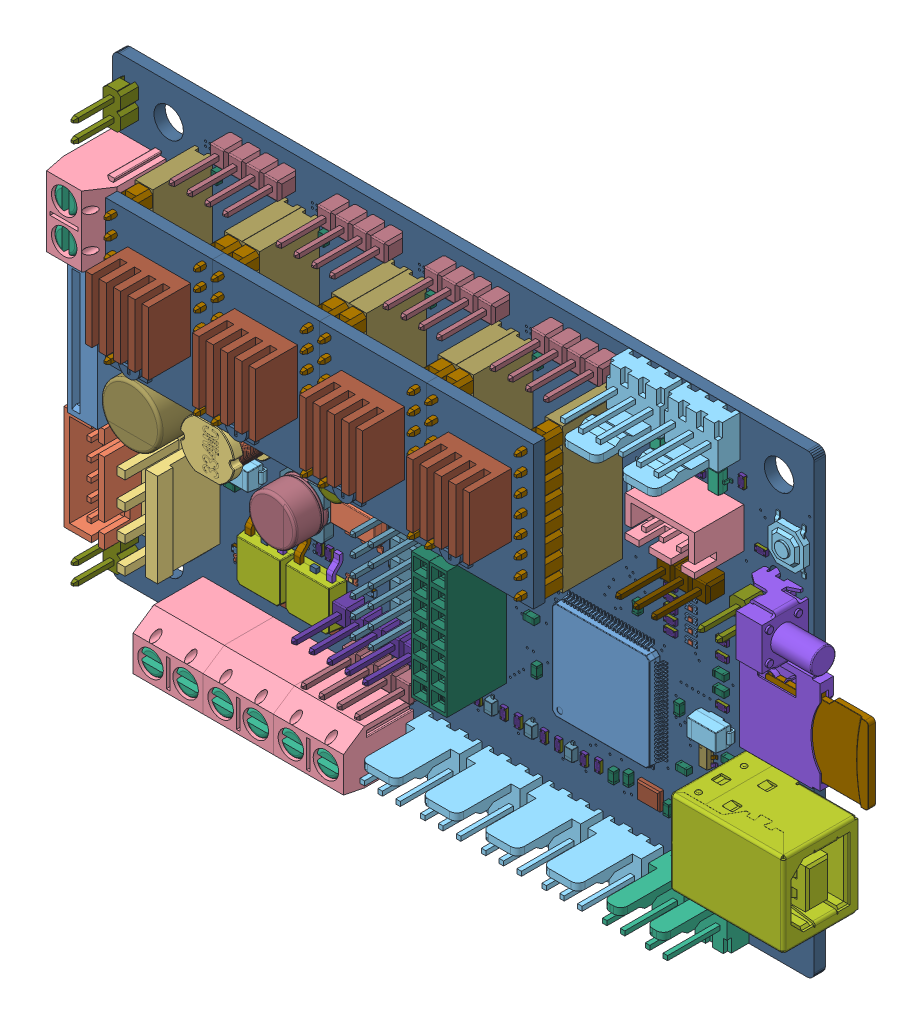
SolidWorks assembly C3D Mini v2, configuration Default. Lengths in mm.
Overall size (109.57 66.19 23.09).
293 component instances, 83 part files, 12 mates.
Components (placement in the parent):
- C3D Mini v2 SMD-1: C3D Mini v2 SMD [Default] at (100 0.95 0) size (90.6 49.98 10.5)
  - Cut-Extrude1-1: Cut-Extrude1 [Default] at (-28.841 21.832 0) x (0 1 0) z (1 0 0) size (16.02 1.55 16.02)
  - Fillet3-1: Fillet3 [Default] at (-64.008 24.638 0) x (0 1 0) z (1 0 0) size (7.02 1.8 6.5)
  - LPattern4-1: LPattern4 [Default] at (-50.673 18.415 0) x (1 0 0) z (0 -1 0) size (2.9 1.5 2.82)
  - Cut-Extrude1-1-1: Cut-Extrude1-1 [Default] at (-70.993 28.702 0) x (0 -1 0) z (-1 0 0) size (4.9 1.5 6.03)
  - Mirror2-1: Mirror2 [Default] at (-23.241 47.879 0) x (0 1 0) z (0 0 1) size (6.5 5.08 1.52)
  - Mirror2-2: Mirror2 [Default] at (-3.187 51.423 0) x (0 1 0) z (0 0 1) size (6.5 5.08 1.52)
  - CirPattern1-1: CirPattern1 [Default] at (-12.942 54.979 0) x (0 -1 0) z (-1 0 0) size (2.9 1.5 2.82)
  - CirPattern1-2: CirPattern1 [Default] at (-21.197 54.979 0) x (0 -1 0) z (-1 0 0) size (2.9 1.5 2.82)
  - Solid1-1: Solid1 [Default] at (-67.56 17.327 0) x (-1 0 0) z (0 0 1) size (6.68 6.2 2.38)
  - Solid1-2: Solid1 [Default] at (-74.545 17.327 0) x (-1 0 0) z (0 0 1) size (6.68 6.2 2.38)
  - Solid2-1: Solid2 [Default] at (-67.56 17.327 0) x (-1 0 0) z (0 0 1) size (0.85 3.15 1.55)
  - Solid2-2: Solid2 [Default] at (-74.545 17.327 0) x (-1 0 0) z (0 0 1) size (0.85 3.15 1.55)
  - Solid3-1: Solid3 [Default] at (-74.545 17.327 0) x (-1 0 0) z (0 0 1) size (0.85 3.15 1.55)
  - Solid3-2: Solid3 [Default] at (-67.56 17.327 0) x (-1 0 0) z (0 0 1) size (0.85 3.15 1.55)
  - Solid4-1: Solid4 [Default] at (-74.545 17.327 0) x (-1 0 0) z (0 0 1) size (0.85 0.8 0.54)
  - Solid4-2: Solid4 [Default] at (-67.56 17.327 0) x (-1 0 0) z (0 0 1) size (0.85 0.8 0.54)
  - Solid5-1: Solid5 [Default] at (-74.545 17.327 0) x (-1 0 0) z (0 0 1) size (5.45 6.25 0.55)
  - Solid5-2: Solid5 [Default] at (-67.56 17.327 0) x (-1 0 0) z (0 0 1) size (5.45 6.25 0.55)
  - Solid1-1-1: Solid1-1 [Default] at (-86.995 33.93 -0.05) x (0 -1 0) z (0 0 1) size (8.5 8.5 10)
  - Solid2-1-1: Solid2-1 [Default] at (-86.995 33.93 -0.05) x (0 -1 0) z (0 0 1) size (8.5 8.5 1.4)
  - Solid3-1-1: Solid3-1 [Default] at (-86.995 33.93 -0.05) x (0 -1 0) z (0 0 1) size (3.45 1 0.7)
  - Solid4-1-1: Solid4-1 [Default] at (-86.995 33.93 -0.05) x (0 -1 0) z (0 0 1) size (3.45 1 0.7)
  - Solid1-2-1: Solid1-2 [Default] at (-61.827 31.242 -0.05) x (-1 0 0) z (0 0 1) size (4.5 4.5 5)
  - Solid2-2-1: Solid2-2 [Default] at (-61.827 31.242 -0.05) x (-1 0 0) z (0 0 1) size (4.5 4.5 1.4)
  - Solid3-2-1: Solid3-2 [Default] at (-61.827 31.242 -0.05) x (-1 0 0) z (0 0 1) size (2.25 0.75 0.7)
  - Solid4-2-1: Solid4-2 [Default] at (-61.827 31.242 -0.05) x (-1 0 0) z (0 0 1) size (2.25 0.75 0.7)
  - _I2-1: _I2 [Default] at (-62.3815 42.0396 0) x (1 0 0) z (0 0 -1) size (6.4 7.16 4.3)
  - _I3-1: _I3 [Default] at (-62.3815 42.0396 0) x (1 0 0) z (0 0 -1) size (7.69 7 7.52)
  - _I4-1: _I4 [Default] at (-62.3815 42.0396 0) x (1 0 0) z (0 0 -1) size (2.09 0.2 5.4)
  - Mirror1-1: Mirror1 [Default] at (-80.403 22.594 0) x (1 0 0) z (0 -1 0) size (5.2 2.4 2.75)
  - Mirror1-2: Mirror1 [Default] at (-72.517 32.766 0) x (-1 0 0) z (0 1 0) size (5.2 2.4 2.75)
  - Mirror1-3: Mirror1 [Default] at (-13.716 23.749 0) x (-1 0 0) z (0 1 0) size (5.2 2.4 2.75)
  - NONE-1: NONE [Default] at (-14.871 21.25 0) x (1 0 0) z (0 -1 0) size (0.54 0.52 0.44)
  - Cut-Extrude4[6]-1: Cut-Extrude4[6] [Default] at (-14.871 21.25 0) x (1 0 0) z (0 -1 0) size (0.54 0.52 0.44)
  - Cut-Extrude4[4]-1: Cut-Extrude4[4] [Default] at (-14.871 21.25 0) x (1 0 0) z (0 -1 0) size (0.54 0.52 0.44)
  - Cut-Extrude4[3]-1: Cut-Extrude4[3] [Default] at (-14.871 21.25 0) x (1 0 0) z (0 -1 0) size (0.54 0.52 0.44)
  - Cut-Extrude4[1]-1: Cut-Extrude4[1] [Default] at (-14.871 21.25 0) x (1 0 0) z (0 -1 0) size (0.54 0.52 0.44)
  - Cut-Extrude4[5]-1: Cut-Extrude4[5] [Default] at (-14.871 21.25 0) x (1 0 0) z (0 -1 0) size (0.54 0.52 0.44)
  - Fillet1-1: Fillet1 [Default] at (-14.871 21.25 0) x (1 0 0) z (0 -1 0) size (1.31 0.94 2.91)
  - Solid1-3-1: Solid1-3 [Default] at (-74.432 22.606 -0.05) size (6.8 6.8 5)
  - Solid2-3-1: Solid2-3 [Default] at (-74.432 22.606 -0.05) size (6.8 6.8 1.4)
  - Solid3-3-1: Solid3-3 [Default] at (-74.432 22.606 -0.05) size (3 0.75 0.7)
  - Solid4-3-1: Solid4-3 [Default] at (-74.432 22.606 -0.05) size (3 0.75 0.7)
  - Split Line4-1: Split Line4 [Default] at (-17.399 39.243 0) x (1 0 0) z (0 -1 0) size (1.6 0.18 0.8)
  - Boss-Extrude2-1: Boss-Extrude2 [Default] at (-17.399 39.243 0) x (1 0 0) z (0 -1 0) size (0.6 0.1 0.5)
  - Split Line4-1-1: Split Line4-1 [Default] at (-17.399 32.258 0) x (1 0 0) z (0 -1 0) size (1.6 0.18 0.8)
  - Split Line4-1-2: Split Line4-1 [Default] at (-17.399 33.655 0) x (1 0 0) z (0 -1 0) size (1.6 0.18 0.8)
  - Split Line4-1-3: Split Line4-1 [Default] at (-17.399 35.052 0) x (1 0 0) z (0 -1 0) size (1.6 0.18 0.8)
  - Split Line4-1-4: Split Line4-1 [Default] at (-17.399 37.846 0) x (1 0 0) z (0 -1 0) size (1.6 0.18 0.8)
  - Split Line4-1-5: Split Line4-1 [Default] at (-17.399 36.449 0) x (1 0 0) z (0 -1 0) size (1.6 0.18 0.8)
  - Split Line4-1-6: Split Line4-1 [Default] at (-8.521 39.993 0) x (1 0 0) z (0 -1 0) size (1.6 0.18 0.8)
  - Boss-Extrude2-1-1: Boss-Extrude2-1 [Default] at (-8.521 39.993 0) x (1 0 0) z (0 -1 0) size (0.6 0.1 0.5)
  - Boss-Extrude2-1-2: Boss-Extrude2-1 [Default] at (-17.399 36.449 0) x (1 0 0) z (0 -1 0) size (0.6 0.1 0.5)
  - Boss-Extrude2-1-3: Boss-Extrude2-1 [Default] at (-17.399 37.846 0) x (1 0 0) z (0 -1 0) size (0.6 0.1 0.5)
  - Boss-Extrude2-1-4: Boss-Extrude2-1 [Default] at (-17.399 35.052 0) x (1 0 0) z (0 -1 0) size (0.6 0.1 0.5)
  - Boss-Extrude2-1-5: Boss-Extrude2-1 [Default] at (-17.399 33.655 0) x (1 0 0) z (0 -1 0) size (0.6 0.1 0.5)
  - Boss-Extrude2-1-6: Boss-Extrude2-1 [Default] at (-17.399 32.258 0) x (1 0 0) z (0 -1 0) size (0.6 0.1 0.5)
  - Boss-Extrude3-1: Boss-Extrude3 [Default] at (-49.415 44.184 0) x (-1 0 0) z (0 1 0) size (7 7.7 6.6)
  - Boss-Extrude3-2: Boss-Extrude3 [Default] at (-64.655 44.184 0) x (-1 0 0) z (0 1 0) size (7 7.7 6.6)
  - Boss-Extrude3-3: Boss-Extrude3 [Default] at (-34.175 44.184 0) x (-1 0 0) z (0 1 0) size (7 7.7 6.6)
  - Boss-Extrude3-4: Boss-Extrude3 [Default] at (-79.895 44.184 0) x (-1 0 0) z (0 1 0) size (7 7.7 6.6)
  - Solid1-4-1: Solid1-4 [Default] at (-13.686 12.407 0) x (-1 0 0) z (0 0 1) size (0.5 0.45 0.55)
  - Solid2-4-1: Solid2-4 [Default] at (-13.686 12.407 0) x (-1 0 0) z (0 0 1) size (0.5 0.45 0.55)
  - Solid3-4-1: Solid3-4 [Default] at (-13.686 12.407 0) x (-1 0 0) z (0 0 1) size (0.5 0.45 0.55)
  - Solid4-4-1: Solid4-4 [Default] at (-13.686 12.407 0) x (-1 0 0) z (0 0 1) size (0.5 0.45 0.55)
  - Solid5-1-1: Solid5-1 [Default] at (-13.686 12.407 0) x (-1 0 0) z (0 0 1) size (3.35 1.69 0.49)
  - Solid6-1: Solid6 [Default] at (-13.686 12.407 0) x (-1 0 0) z (0 0 1) size (3.18 1.09 0.08)
  - Solid7-1: Solid7 [Default] at (-13.686 12.407 0) x (-1 0 0) z (0 0 1) size (0.72 0.45 0.55)
  - Solid8-1: Solid8 [Default] at (-13.686 12.407 0) x (-1 0 0) z (0 0 1) size (0.72 0.45 0.55)
  - Solid9-1: Solid9 [Default] at (-13.686 12.407 0) x (-1 0 0) z (0 0 1) size (0.73 0.45 0.55)
  - Solid10-1: Solid10 [Default] at (-13.686 12.407 0) x (-1 0 0) z (0 0 1) size (0.73 0.45 0.55)
  - Boss-Extrude2-2-1: Boss-Extrude2-2 [Default] at (-51.423 10.299 0) x (0 -1 0) z (-1 0 0) size (2.5 0.8 1.25)
  - Boss-Extrude2-2-2: Boss-Extrude2-2 [Default] at (-45.708 10.299 0) x (0 -1 0) z (-1 0 0) size (2.5 0.8 1.25)
  - Boss-Extrude2-2-3: Boss-Extrude2-2 [Default] at (-34.278 10.299 0) x (0 -1 0) z (-1 0 0) size (2.5 0.8 1.25)
  - Boss-Extrude2-2-4: Boss-Extrude2-2 [Default] at (-39.993 10.299 0) x (0 -1 0) z (-1 0 0) size (2.5 0.8 1.25)
  - Mirror1-1-1: Mirror1-1 [Default] at (-12.839 30.722 0) x (1 0 0) z (0 -1 0) size (1.6 0.82 0.82)
  - Mirror1-1-2: Mirror1-1 [Default] at (-18.796 23.622 0) x (0 1 0) z (1 0 0) size (1.6 0.82 0.82)
  - Mirror1-1-3: Mirror1-1 [Default] at (-20.32 10.414 0) x (0 1 0) z (1 0 0) size (1.6 0.82 0.82)
  - Mirror1-1-4: Mirror1-1 [Default] at (-26.047 11.291 0) x (0 1 0) z (1 0 0) size (1.6 0.82 0.82)
  - Mirror1-1-5: Mirror1-1 [Default] at (-13.589 7.874 0) x (0 -1 0) z (-1 0 0) size (1.6 0.82 0.82)
  - Mirror1-1-6: Mirror1-1 [Default] at (-61.2895 27.8645 0) x (0 1 0) z (1 0 0) size (1.6 0.82 0.82)
  - Mirror1-1-7: Mirror1-1 [Default] at (-28.182 10.553 0) x (0 1 0) z (1 0 0) size (1.6 0.82 0.82)
  - Mirror1-1-8: Mirror1-1 [Default] at (-53.479 39.485 0) x (1 0 0) z (0 -1 0) size (1.6 0.82 0.82)
  - Mirror1-1-9: Mirror1-1 [Default] at (-39.128 18.0982 0) x (0 1 0) z (1 0 0) size (1.6 0.82 0.82)
  - Mirror1-1-10: Mirror1-1 [Default] at (-15.621 7.874 0) x (0 -1 0) z (-1 0 0) size (1.6 0.82 0.82)
  - Mirror1-1-11: Mirror1-1 [Default] at (-11.684 14.605 0) x (1 0 0) z (0 -1 0) size (1.6 0.82 0.82)
  - Mirror1-1-12: Mirror1-1 [Default] at (-69.481 56.249 0) x (0 -1 0) z (-1 0 0) size (1.6 0.82 0.82)
  - Mirror1-1-13: Mirror1-1 [Default] at (-18.796 10.668 0) x (0 1 0) z (1 0 0) size (1.6 0.82 0.82)
  - Mirror1-1-14: Mirror1-1 [Default] at (-39.89 24.1688 0) x (1 0 0) z (0 -1 0) size (1.6 0.82 0.82)
  - Mirror1-1-15: Mirror1-1 [Default] at (-33.6035 33.135 0) x (0 1 0) z (1 0 0) size (1.6 0.82 0.82)
  - Mirror1-1-16: Mirror1-1 [Default] at (-11.684 20.701 0) x (1 0 0) z (0 -1 0) size (1.6 0.82 0.82)
  - Mirror1-1-17: Mirror1-1 [Default] at (-18.149 16.4472 0) x (1 0 0) z (0 -1 0) size (1.6 0.82 0.82)
  - Mirror1-1-18: Mirror1-1 [Default] at (-82.55 19.304 0) x (1 0 0) z (0 -1 0) size (1.6 0.82 0.82)
  - Mirror1-1-19: Mirror1-1 [Default] at (-24.7135 33.135 0) x (0 1 0) z (1 0 0) size (1.6 0.82 0.82)
  - Mirror1-1-20: Mirror1-1 [Default] at (-50.8 15.494 0) x (1 0 0) z (0 -1 0) size (1.6 0.82 0.82)
  - Mirror1-1-21: Mirror1-1 [Default] at (-39.001 56.249 0) x (0 -1 0) z (-1 0 0) size (1.6 0.82 0.82)
  - Mirror1-1-22: Mirror1-1 [Default] at (-83.959 39.485 0) x (1 0 0) z (0 -1 0) size (1.6 0.82 0.82)
  - Mirror1-1-23: Mirror1-1 [Default] at (-84.721 56.249 0) x (0 -1 0) z (-1 0 0) size (1.6 0.82 0.82)
  - Mirror1-1-24: Mirror1-1 [Default] at (-68.719 39.485 0) x (1 0 0) z (0 -1 0) size (1.6 0.82 0.82)
  - Mirror1-1-25: Mirror1-1 [Default] at (-12.839 28.69 0) x (1 0 0) z (0 -1 0) size (1.6 0.82 0.82)
  - Mirror1-1-26: Mirror1-1 [Default] at (-38.239 39.485 0) x (1 0 0) z (0 -1 0) size (1.6 0.82 0.82)
  - Mirror1-1-27: Mirror1-1 [Default] at (-54.241 56.249 0) x (0 -1 0) z (-1 0 0) size (1.6 0.82 0.82)
  - Boss-Extrude3-1-1: Boss-Extrude3-1 [Default] at (-34.81 39.885 0) x (1 0 0) z (0 -1 0) size (1.54 0.39 0.8)
  - Boss-Extrude3-1-2: Boss-Extrude3-1 [Default] at (-12.839 27.058 0) x (1 0 0) z (0 -1 0) size (1.54 0.39 0.8)
  - Boss-Extrude3-1-3: Boss-Extrude3-1 [Default] at (-47.213 10.299 0) x (0 -1 0) z (-1 0 0) size (1.54 0.39 0.8)
  - Boss-Extrude3-1-4: Boss-Extrude3-1 [Default] at (-80.53 39.885 0) x (1 0 0) z (0 -1 0) size (1.54 0.39 0.8)
  - Boss-Extrude3-1-5: Boss-Extrude3-1 [Default] at (-20.193 39.643 0) x (1 0 0) z (0 -1 0) size (1.54 0.39 0.8)
  - Boss-Extrude3-1-6: Boss-Extrude3-1 [Default] at (-12.839 33.154 0) x (1 0 0) z (0 -1 0) size (1.54 0.39 0.8)
  - Boss-Extrude3-1-7: Boss-Extrude3-1 [Default] at (-9.5822 55.88 0) x (0 -1 0) z (-1 0 0) size (1.54 0.39 0.8)
  - Boss-Extrude3-1-8: Boss-Extrude3-1 [Default] at (-49.384 22.225 0) x (0 -1 0) z (-1 0 0) size (1.54 0.39 0.8)
  - Boss-Extrude3-1-9: Boss-Extrude3-1 [Default] at (-12.839 35.186 0) x (1 0 0) z (0 -1 0) size (1.54 0.39 0.8)
  - Boss-Extrude3-1-10: Boss-Extrude3-1 [Default] at (-68.434 17.526 0) x (0 -1 0) z (-1 0 0) size (1.54 0.39 0.8)
  - Boss-Extrude3-1-11: Boss-Extrude3-1 [Default] at (-20.193 38.246 0) x (1 0 0) z (0 -1 0) size (1.54 0.39 0.8)
  - Boss-Extrude3-1-12: Boss-Extrude3-1 [Default] at (-46.621 39.25 0) x (1 0 0) z (0 -1 0) size (1.54 0.39 0.8)
  - Boss-Extrude3-1-13: Boss-Extrude3-1 [Default] at (-61.861 39.25 0) x (1 0 0) z (0 -1 0) size (1.54 0.39 0.8)
  - Boss-Extrude3-1-14: Boss-Extrude3-1 [Default] at (-41.498 10.299 0) x (0 -1 0) z (-1 0 0) size (1.54 0.39 0.8)
  - Boss-Extrude3-1-15: Boss-Extrude3-1 [Default] at (-31.381 39.25 0) x (1 0 0) z (0 -1 0) size (1.54 0.39 0.8)
  - Boss-Extrude3-1-16: Boss-Extrude3-1 [Default] at (-52.928 10.299 0) x (0 -1 0) z (-1 0 0) size (1.54 0.39 0.8)
  - Boss-Extrude3-1-17: Boss-Extrude3-1 [Default] at (-49.245 10.299 0) x (0 -1 0) z (-1 0 0) size (1.54 0.39 0.8)
  - Boss-Extrude3-1-18: Boss-Extrude3-1 [Default] at (-24.499 54.363 0) x (1 0 0) z (0 -1 0) size (1.54 0.39 0.8)
  - Boss-Extrude3-1-19: Boss-Extrude3-1 [Default] at (-76.7271 17.526 0) x (0 -1 0) z (-1 0 0) size (1.54 0.39 0.8)
  - Boss-Extrude3-1-20: Boss-Extrude3-1 [Default] at (-20.193 32.658 0) x (1 0 0) z (0 -1 0) size (1.54 0.39 0.8)
  - Boss-Extrude3-1-21: Boss-Extrude3-1 [Default] at (-11.684 12.973 0) x (1 0 0) z (0 -1 0) size (1.54 0.39 0.8)
  - Boss-Extrude3-1-22: Boss-Extrude3-1 [Default] at (-6.489 44.965 0) x (1 0 0) z (0 -1 0) size (1.54 0.39 0.8)
  - Boss-Extrude3-1-23: Boss-Extrude3-1 [Default] at (-20.193 35.452 0) x (1 0 0) z (0 -1 0) size (1.54 0.39 0.8)
  - Boss-Extrude3-1-24: Boss-Extrude3-1 [Default] at (-20.193 34.055 0) x (1 0 0) z (0 -1 0) size (1.54 0.39 0.8)
  - Boss-Extrude3-1-25: Boss-Extrude3-1 [Default] at (-24.499 56.395 0) x (1 0 0) z (0 -1 0) size (1.54 0.39 0.8)
  - Boss-Extrude3-1-26: Boss-Extrude3-1 [Default] at (-22.352 44.088 0) x (1 0 0) z (0 -1 0) size (1.54 0.39 0.8)
  - Boss-Extrude3-1-27: Boss-Extrude3-1 [Default] at (-32.1 10.299 0) x (0 -1 0) z (-1 0 0) size (1.54 0.39 0.8)
  - Boss-Extrude3-1-28: Boss-Extrude3-1 [Default] at (-65.29 39.885 0) x (1 0 0) z (0 -1 0) size (1.54 0.39 0.8)
  - Boss-Extrude3-1-29: Boss-Extrude3-1 [Default] at (-50.05 39.885 0) x (1 0 0) z (0 -1 0) size (1.54 0.39 0.8)
  - Boss-Extrude3-1-30: Boss-Extrude3-1 [Default] at (-30.068 10.553 0) x (0 -1 0) z (-1 0 0) size (1.54 0.39 0.8)
  - Boss-Extrude3-1-31: Boss-Extrude3-1 [Default] at (-75.419 17.526 0) x (0 -1 0) z (-1 0 0) size (1.54 0.39 0.8)
  - Boss-Extrude3-1-32: Boss-Extrude3-1 [Default] at (-43.53 10.299 0) x (0 -1 0) z (-1 0 0) size (1.54 0.39 0.8)
  - Boss-Extrude3-1-33: Boss-Extrude3-1 [Default] at (-11.684 17.037 0) x (1 0 0) z (0 -1 0) size (1.54 0.39 0.8)
  - Boss-Extrude3-1-34: Boss-Extrude3-1 [Default] at (-8.521 39.123 0) x (1 0 0) z (0 -1 0) size (1.54 0.39 0.8)
  - Boss-Extrude3-1-35: Boss-Extrude3-1 [Default] at (-69.7421 17.526 0) x (0 -1 0) z (-1 0 0) size (1.54 0.39 0.8)
  - Boss-Extrude3-1-36: Boss-Extrude3-1 [Default] at (-16.244 56.3315 0) x (1 0 0) z (0 -1 0) size (1.54 0.39 0.8)
  - Boss-Extrude3-1-37: Boss-Extrude3-1 [Default] at (-37.815 10.299 0) x (0 -1 0) z (-1 0 0) size (1.54 0.39 0.8)
  - Boss-Extrude3-1-38: Boss-Extrude3-1 [Default] at (-20.193 36.849 0) x (1 0 0) z (0 -1 0) size (1.54 0.39 0.8)
  - Boss-Extrude3-1-39: Boss-Extrude3-1 [Default] at (-35.783 10.299 0) x (0 -1 0) z (-1 0 0) size (1.54 0.39 0.8)
  - Boss-Extrude3-1-40: Boss-Extrude3-1 [Default] at (-77.101 39.25 0) x (1 0 0) z (0 -1 0) size (1.54 0.39 0.8)
  - Boss-Extrude3-1-41: Boss-Extrude3-1 [Default] at (-7.251 49.156 0) x (1 0 0) z (0 -1 0) size (1.54 0.39 0.8)
  - Boss-Extrude3-1-42: Boss-Extrude3-1 [Default] at (-16.244 54.2995 0) x (1 0 0) z (0 -1 0) size (1.54 0.39 0.8)
  - Boss-Extrude3-1-43: Boss-Extrude3-1 [Default] at (-11.684 19.069 0) x (1 0 0) z (0 -1 0) size (1.54 0.39 0.8)
  - Split Line1-1: Split Line1 [Default] at (-11.684 12.973 0) x (1 0 0) z (0 -1 0) size (1.6 0.45 0.8)
  - Split Line1-2: Split Line1 [Default] at (-11.684 19.069 0) x (1 0 0) z (0 -1 0) size (1.6 0.45 0.8)
  - Split Line1-3: Split Line1 [Default] at (-37.815 10.299 0) x (0 -1 0) z (-1 0 0) size (1.6 0.45 0.8)
  - Split Line1-4: Split Line1 [Default] at (-24.499 54.363 0) x (1 0 0) z (0 -1 0) size (1.6 0.45 0.8)
  - Split Line1-5: Split Line1 [Default] at (-20.193 34.055 0) x (1 0 0) z (0 -1 0) size (1.6 0.45 0.8)
  - Split Line1-6: Split Line1 [Default] at (-35.783 10.299 0) x (0 -1 0) z (-1 0 0) size (1.6 0.45 0.8)
  - Split Line1-7: Split Line1 [Default] at (-7.251 49.156 0) x (1 0 0) z (0 -1 0) size (1.6 0.45 0.8)
  - Split Line1-8: Split Line1 [Default] at (-16.244 56.3315 0) x (1 0 0) z (0 -1 0) size (1.6 0.45 0.8)
  - Split Line1-9: Split Line1 [Default] at (-16.244 54.2995 0) x (1 0 0) z (0 -1 0) size (1.6 0.45 0.8)
  - Split Line1-10: Split Line1 [Default] at (-20.193 36.849 0) x (1 0 0) z (0 -1 0) size (1.6 0.45 0.8)
  - Split Line1-11: Split Line1 [Default] at (-61.861 39.25 0) x (1 0 0) z (0 -1 0) size (1.6 0.45 0.8)
  - Split Line1-12: Split Line1 [Default] at (-6.489 44.965 0) x (1 0 0) z (0 -1 0) size (1.6 0.45 0.8)
  - Split Line1-13: Split Line1 [Default] at (-20.193 38.246 0) x (1 0 0) z (0 -1 0) size (1.6 0.45 0.8)
  - Split Line1-14: Split Line1 [Default] at (-12.839 27.058 0) x (1 0 0) z (0 -1 0) size (1.6 0.45 0.8)
  - Split Line1-15: Split Line1 [Default] at (-69.7421 17.526 0) x (0 -1 0) z (-1 0 0) size (1.6 0.45 0.8)
  - Split Line1-16: Split Line1 [Default] at (-20.193 32.658 0) x (1 0 0) z (0 -1 0) size (1.6 0.45 0.8)
  - Split Line1-17: Split Line1 [Default] at (-22.352 44.088 0) x (1 0 0) z (0 -1 0) size (1.6 0.45 0.8)
  - Split Line1-18: Split Line1 [Default] at (-49.384 22.225 0) x (0 -1 0) z (-1 0 0) size (1.6 0.45 0.8)
  - Split Line1-19: Split Line1 [Default] at (-65.29 39.885 0) x (1 0 0) z (0 -1 0) size (1.6 0.45 0.8)
  - Split Line1-20: Split Line1 [Default] at (-75.419 17.526 0) x (0 -1 0) z (-1 0 0) size (1.6 0.45 0.8)
  - Split Line1-21: Split Line1 [Default] at (-77.101 39.25 0) x (1 0 0) z (0 -1 0) size (1.6 0.45 0.8)
  - Split Line1-22: Split Line1 [Default] at (-34.81 39.885 0) x (1 0 0) z (0 -1 0) size (1.6 0.45 0.8)
  - Split Line1-23: Split Line1 [Default] at (-20.193 35.452 0) x (1 0 0) z (0 -1 0) size (1.6 0.45 0.8)
  - Split Line1-24: Split Line1 [Default] at (-50.05 39.885 0) x (1 0 0) z (0 -1 0) size (1.6 0.45 0.8)
  - Split Line1-25: Split Line1 [Default] at (-9.5822 55.88 0) x (0 -1 0) z (-1 0 0) size (1.6 0.45 0.8)
  - Split Line1-26: Split Line1 [Default] at (-43.53 10.299 0) x (0 -1 0) z (-1 0 0) size (1.6 0.45 0.8)
  - Split Line1-27: Split Line1 [Default] at (-46.621 39.25 0) x (1 0 0) z (0 -1 0) size (1.6 0.45 0.8)
  - Split Line1-28: Split Line1 [Default] at (-41.498 10.299 0) x (0 -1 0) z (-1 0 0) size (1.6 0.45 0.8)
  - Split Line1-29: Split Line1 [Default] at (-8.521 39.123 0) x (1 0 0) z (0 -1 0) size (1.6 0.45 0.8)
  - Split Line1-30: Split Line1 [Default] at (-68.434 17.526 0) x (0 -1 0) z (-1 0 0) size (1.6 0.45 0.8)
  - Split Line1-31: Split Line1 [Default] at (-52.928 10.299 0) x (0 -1 0) z (-1 0 0) size (1.6 0.45 0.8)
  - Split Line1-32: Split Line1 [Default] at (-24.499 56.395 0) x (1 0 0) z (0 -1 0) size (1.6 0.45 0.8)
  - Split Line1-33: Split Line1 [Default] at (-47.213 10.299 0) x (0 -1 0) z (-1 0 0) size (1.6 0.45 0.8)
  - Split Line1-34: Split Line1 [Default] at (-20.193 39.643 0) x (1 0 0) z (0 -1 0) size (1.6 0.45 0.8)
  - Split Line1-35: Split Line1 [Default] at (-31.381 39.25 0) x (1 0 0) z (0 -1 0) size (1.6 0.45 0.8)
  - Split Line1-36: Split Line1 [Default] at (-76.7271 17.526 0) x (0 -1 0) z (-1 0 0) size (1.6 0.45 0.8)
  - Split Line1-37: Split Line1 [Default] at (-49.245 10.299 0) x (0 -1 0) z (-1 0 0) size (1.6 0.45 0.8)
  - Split Line1-38: Split Line1 [Default] at (-32.1 10.299 0) x (0 -1 0) z (-1 0 0) size (1.6 0.45 0.8)
  - Split Line1-39: Split Line1 [Default] at (-12.839 33.154 0) x (1 0 0) z (0 -1 0) size (1.6 0.45 0.8)
  - Split Line1-40: Split Line1 [Default] at (-30.068 10.553 0) x (0 -1 0) z (-1 0 0) size (1.6 0.45 0.8)
  - Split Line1-41: Split Line1 [Default] at (-11.684 17.037 0) x (1 0 0) z (0 -1 0) size (1.6 0.45 0.8)
  - Split Line1-42: Split Line1 [Default] at (-80.53 39.885 0) x (1 0 0) z (0 -1 0) size (1.6 0.45 0.8)
  - Split Line1-43: Split Line1 [Default] at (-12.839 35.186 0) x (1 0 0) z (0 -1 0) size (1.6 0.45 0.8)
  - Boss-Extrude3-2-1: Boss-Extrude3-2 [Default] at (-59.417 21.082 0) x (0 -1 0) z (-1 0 0) size (1.54 0.39 0.8)
  - Boss-Extrude3-2-2: Boss-Extrude3-2 [Default] at (-63.119 16.148 0) x (1 0 0) z (0 -1 0) size (1.54 0.39 0.8)
  - Boss-Extrude3-2-3: Boss-Extrude3-2 [Default] at (-59.417 24.638 0) x (0 -1 0) z (-1 0 0) size (1.54 0.39 0.8)
  - Boss-Extrude3-2-4: Boss-Extrude3-2 [Default] at (-81.788 11.83 0) x (1 0 0) z (0 -1 0) size (1.54 0.39 0.8)
  - Split Line1-1-1: Split Line1-1 [Default] at (-59.417 24.638 0) x (0 -1 0) z (-1 0 0) size (1.6 0.45 0.8)
  - Split Line1-1-2: Split Line1-1 [Default] at (-59.417 21.082 0) x (0 -1 0) z (-1 0 0) size (1.6 0.45 0.8)
  - Split Line1-1-3: Split Line1-1 [Default] at (-63.119 16.148 0) x (1 0 0) z (0 -1 0) size (1.6 0.45 0.8)
  - Split Line1-1-4: Split Line1-1 [Default] at (-81.788 11.83 0) x (1 0 0) z (0 -1 0) size (1.6 0.45 0.8)
  - Split Line4-2-1: Split Line4-2 [Default] at (-81.788 10.16 0) x (1 0 0) z (0 -1 0) size (1.6 0.18 0.8)
  - Split Line4-2-2: Split Line4-2 [Default] at (-65.786 15.748 0) x (1 0 0) z (0 -1 0) size (1.6 0.18 0.8)
  - Boss-Extrude2-3-1: Boss-Extrude2-3 [Default] at (-81.788 10.16 0) x (1 0 0) z (0 -1 0) size (0.6 0.1 0.5)
  - Boss-Extrude2-3-2: Boss-Extrude2-3 [Default] at (-65.786 15.748 0) x (1 0 0) z (0 -1 0) size (0.6 0.1 0.5)
- DG301-5.0-02 (OPTION 1)-1: DG301-5.0-02 (OPTION 1) [Default] at (3.11 52.82 0) x (0 -1 0) z (0 0 1) size (10.6 7.6 14.4)
  - DG301-5.0-02-body-1: DG301-5.0-02-body [Default] at origin size (10.6 7.6 10)
  - DG301-5.0-pin-1: DG301-5.0-pin [Default] at (0 0.5 2.85) size (3.9 4 9.9)
  - DG301-5.0-pin-2: DG301-5.0-pin [Default] at (5 0.5 2.85) size (3.9 4 9.9)
  - DG301-5.0-screw-1: DG301-5.0-screw [Default] at (5 0 4) size (3.6 3.6 5.84)
  - DG301-5.0-screw-2: DG301-5.0-screw [Default] at (0 0 4) size (3.6 3.6 5.84)
  - DG301-5.0-wire_prot-1: DG301-5.0-wire_prot [Default] at (5 0 5.5) size (3.9 5.45 2.85)
  - DG301-5.0-wire_prot-2: DG301-5.0-wire_prot [Default] at (0 0 5.5) size (3.9 5.45 2.85)
- DG301-5.0-02 (OPTION 1)-1-1: DG301-5.0-02 (OPTION 1)-1 [Default] at (15.42 1.91 0) size (10.6 7.6 14.4)
  - DG301-5.0-02-body-1: DG301-5.0-02-body [Default] at origin size (10.6 7.6 10)
  - DG301-5.0-pin-1: DG301-5.0-pin [Default] at (0 0.5 2.85) size (3.9 4 9.9)
  - DG301-5.0-pin-2: DG301-5.0-pin [Default] at (5 0.5 2.85) size (3.9 4 9.9)
  - DG301-5.0-screw-1: DG301-5.0-screw [Default] at (0 0 4) size (3.6 3.6 5.84)
  - DG301-5.0-screw-2: DG301-5.0-screw [Default] at (5 0 4) size (3.6 3.6 5.84)
  - DG301-5.0-wire_prot-1: DG301-5.0-wire_prot [Default] at (0 0 5.5) size (3.9 5.45 2.85)
  - DG301-5.0-wire_prot-2: DG301-5.0-wire_prot [Default] at (5 0 5.5) size (3.9 5.45 2.85)
- DG301-5.0-02 (OPTION 1)-2-1: DG301-5.0-02 (OPTION 1)-2 [Default] at (25.42 1.91 0) size (10.6 7.6 14.4)
  - DG301-5.0-02-body-1: DG301-5.0-02-body [Default] at origin size (10.6 7.6 10)
  - DG301-5.0-pin-1: DG301-5.0-pin [Default] at (0 0.5 2.85) size (3.9 4 9.9)
  - DG301-5.0-pin-2: DG301-5.0-pin [Default] at (5 0.5 2.85) size (3.9 4 9.9)
  - DG301-5.0-screw-1: DG301-5.0-screw [Default] at (0 0 4) size (3.6 3.6 5.84)
  - DG301-5.0-screw-2: DG301-5.0-screw [Default] at (5 0 4) size (3.6 3.6 5.84)
  - DG301-5.0-wire_prot-1: DG301-5.0-wire_prot [Default] at (5 0 5.5) size (3.9 5.45 2.85)
  - DG301-5.0-wire_prot-2: DG301-5.0-wire_prot [Default] at (0 0 5.5) size (3.9 5.45 2.85)
- DG301-5.0-02 (OPTION 1)-3-1: DG301-5.0-02 (OPTION 1)-3 [Default] at (35.42 1.91 0) size (10.6 7.6 14.4)
  - DG301-5.0-02-body-1: DG301-5.0-02-body [Default] at origin size (10.6 7.6 10)
  - DG301-5.0-pin-1: DG301-5.0-pin [Default] at (5 0.5 2.85) size (3.9 4 9.9)
  - DG301-5.0-pin-2: DG301-5.0-pin [Default] at (0 0.5 2.85) size (3.9 4 9.9)
  - DG301-5.0-screw-1: DG301-5.0-screw [Default] at (5 0 4) size (3.6 3.6 5.84)
  - DG301-5.0-screw-2: DG301-5.0-screw [Default] at (0 0 4) size (3.6 3.6 5.84)
  - DG301-5.0-wire_prot-1: DG301-5.0-wire_prot [Default] at (5 0 5.5) size (3.9 5.45 2.85)
  - DG301-5.0-wire_prot-2: DG301-5.0-wire_prot [Default] at (0 0 5.5) size (3.9 5.45 2.85)
- SD SLot Assembly-1: SD SLot Assembly [Default] at (68.9232 25.4319 -11.7384) x (-1 0 0) z (0 0 1) size (19.43 14.95 2.45)
  - SD Slot-1: SD Slot [Default] at (-32.2702 -6.7777 11.7384) size (12.6 14.95 2.45)
  - micro_sd_card-1: micro_sd_card [Default] at (-40.6508 -12.1921 12.5884) x (1 0 0) z (0 -1 0) size (15 1.05 11.24)
- c3d mini Board v2-1: c3d mini Board v2 [Default] at (100 1 -1.6) size (100 65 1.6)
- 12MHZ Crystal PN X322512MMB4SC-1: 12MHZ Crystal PN X322512MMB4SC [Default] at (76.95 11.61 0) x (1 0 0) z (0 -1 0) size (3.2 0.7 2.5)
- female_header_a-bl254-eg-g08d-1: female_header_a-bl254-eg-g08d [Default] at (40.93 48.74 0) x (0 1 0) z (1 0 0) size (20.57 11.65 2.5)
- female_header_a-bl254-eg-g08d-2: female_header_a-bl254-eg-g08d [Default] at (56.17 48.74 0) x (0 1 0) z (1 0 0) size (20.57 11.65 2.5)
- female_header_a-bl254-eg-g08d-3: female_header_a-bl254-eg-g08d [Default] at (25.69 48.74 0) x (0 1 0) z (1 0 0) size (20.57 11.65 2.5)
- female_header_a-bl254-eg-g08d-4: female_header_a-bl254-eg-g08d [Default] at (28.23 48.74 0) x (0 1 0) z (1 0 0) size (20.57 11.65 2.5)
- female_header_a-bl254-eg-g08d-5: female_header_a-bl254-eg-g08d [Default] at (58.71 48.74 0) x (0 1 0) z (1 0 0) size (20.57 11.65 2.5)
- female_header_a-bl254-eg-g08d-6: female_header_a-bl254-eg-g08d [Default] at (43.47 48.74 0) x (0 1 0) z (1 0 0) size (20.57 11.65 2.5)
- female_header_a-bl254-eg-g08d-7: female_header_a-bl254-eg-g08d [Default] at (71.41 48.74 0) x (0 1 0) z (1 0 0) size (20.57 11.65 2.5)
- female_header_a-bl254-eg-g08d-8: female_header_a-bl254-eg-g08d [Default] at (12.99 48.74 0) x (0 1 0) z (1 0 0) size (20.57 11.65 2.5)
- Pin Header 1x4 TH Pitch 2.54mm-1: Pin Header 1x4 TH Pitch 2.54mm [Default] at (17.6898 61.95 -0.0015) x (1 0 -0.000037) z (0.000037 0 1) size (10.16 2.54 12.7)
- Pin Header 1x4 TH Pitch 2.54mm-2: Pin Header 1x4 TH Pitch 2.54mm [Default] at (32.9298 61.95 -0.0015) x (1 0 -0.000037) z (0.000037 0 1) size (10.16 2.54 12.7)
- Pin Header 1x4 TH Pitch 2.54mm-3: Pin Header 1x4 TH Pitch 2.54mm [Default] at (36.4998 9.26 -0.0015) x (1 0 -0.000037) z (0.000037 0 1) size (10.16 2.54 12.7)
- Pin Header 1x4 TH Pitch 2.54mm-4: Pin Header 1x4 TH Pitch 2.54mm [Default] at (48.1698 61.95 -0.0015) x (1 0 -0.000037) z (0.000037 0 1) size (10.16 2.54 12.7)
- Pin Header 1x4 TH Pitch 2.54mm-5: Pin Header 1x4 TH Pitch 2.54mm [Default] at (63.4098 61.95 -0.0015) x (1 0 -0.000037) z (0.000037 0 1) size (10.16 2.54 12.7)
- Pin Header 2x6 TH Pitch 2.54mm-1: Pin Header 2x6 TH Pitch 2.54mm [Default] at (44.75 31.4802 -0.0009) x (0 -1 -0.000037) z (0 -0.000037 1) size (15.24 5.08 12.7)
- female_header_a-bl254-eg-g07d-1: female_header_a-bl254-eg-g07d [Default] at (52.38 25.13 0) x (0 1 0) z (1 0 0) size (18.03 11.65 2.5)
- female_header_a-bl254-eg-g07d-2: female_header_a-bl254-eg-g07d [Default] at (54.91 25.13 0) x (0 1 0) z (1 0 0) size (18.03 11.65 2.5)
- pin_header_aw140-eg-g02d-1: pin_header_aw140-eg-g02d [Default] at (2.46 13.19 0) x (0 1 0) z (-1 0 0) size (5.08 11.2 2.5)
- pin_header_aw140-eg-g02d-2: pin_header_aw140-eg-g02d [Default] at (85.39 43.24 0) x (-1 0 0) z (0 -1 0) size (5.08 11.2 2.5)
- pin_header_aw140-eg-g02d-3: pin_header_aw140-eg-g02d [Default] at (2.46 67.8 0) x (0 1 0) z (-1 0 0) size (5.08 11.2 2.5)
- Pin Header 1x5 TH Pitch 2.54mm-1: Pin Header 1x5 TH Pitch 2.54mm [Default] at (35.0998 14.08 -0.0014) x (1 0 -0.000037) z (0.000037 0 1) size (12.7 2.54 12.7)
- Pin Header 1x3 TH Pitch 2.54mm-1: Pin Header 1x3 TH Pitch 2.54mm [Default] at (81.3298 42.78 -0.0012) x (1 0 -0.000037) z (0.000037 0 1) size (7.62 2.54 12.7)
- c-1-84534-2-e-3d (FFC1)-1: c-1-84534-2-e-3d (FFC1) [Default] at (3.505 34.165 7.8) x (0 -1 0) z (0 0 1) size (18.75 4.8 11)
- B5B-XH-A (U$12)-1: B5B-XH-A (U$12) [Default] at (2.95 17.04 0) x (0 1 0) z (1 0 0) size (14.9 10.4 5.75)
- B4P-VH (CN1)-1: B4P-VH (CN1) [Default] at (11.57 18.27 0) x (0 -1 0) z (-1 0 0) size (15.78 14.6 8.5)
- B3B-XH-A (U$11)-1: B3B-XH-A (U$11) [Default] at (85.02 50.93 0) x (1 0 0) z (0 -1 0) size (9.9 10.4 5.75)
- c-640454-3-aa-3d (POLAR 3 PIN)-1: c-640454-3-aa-3d (POLAR 3 PIN) [Default] at (74.73 3.05 1.5875) x (1 0 0) z (0 -1 0) size (7.62 14.49 5.84)
- c-640454-3-aa-3d (POLAR 3 PIN)-2: c-640454-3-aa-3d (POLAR 3 PIN) [Default] at (77.38 61.95 1.5875) x (-1 0 0) z (0 1 0) size (7.62 14.49 5.84)
- c-640454-3-aa-3d (POLAR 3 PIN)-3: c-640454-3-aa-3d (POLAR 3 PIN) [Default] at (48.82 3.03 1.5875) x (1 0 0) z (0 -1 0) size (7.62 14.49 5.84)
- c-640454-3-aa-3d (POLAR 3 PIN)-4: c-640454-3-aa-3d (POLAR 3 PIN) [Default] at (66.09 3.05 1.5875) x (1 0 0) z (0 -1 0) size (7.62 14.49 5.84)
- c-640454-3-aa-3d (POLAR 3 PIN)-5: c-640454-3-aa-3d (POLAR 3 PIN) [Default] at (85.64 61.95 1.5875) x (-1 0 0) z (0 1 0) size (7.62 14.49 5.84)
- c-640454-3-aa-3d (POLAR 3 PIN)-6: c-640454-3-aa-3d (POLAR 3 PIN) [Default] at (57.45 3.05 1.5875) x (1 0 0) z (0 -1 0) size (7.62 14.49 5.84)
- c-640454-2-aa-3d (POLAR 2 PIN)-1: c-640454-2-aa-3d (POLAR 2 PIN) [Default] at (82.09 3.05 1.5875) x (1 0 0) z (0 -1 0) size (5.08 14.49 5.84)
- c-640454-2-aa-3d (POLAR 2 PIN)-2: c-640454-2-aa-3d (POLAR 2 PIN) [Default] at (88.19 3.05 1.5875) x (1 0 0) z (0 -1 0) size (5.08 14.49 5.84)
- WURTH_61400416121 (USB JACK)-1: WURTH_61400416121 (USB JACK) [Default] at (92.53 17.88 0) x (0 1 0) z (1 0 0) size (14.95 14.22 16.5)
- c-1-1825027-1-g1-3d-1: c-1-1825027-1-g1-3d [Default] at (99.5662 44.1779 4.0132) x (0 1 0) z (1 0 0) size (8.41 10.52 12.36)
- Driver-1: Driver [Default] at (19.34 48.74 11.04) x (0 -1 0) z (-1 0 0) size (20.32 15.85 15.24)
  - pin_header_aw140-eg-g08d-1: pin_header_aw140-eg-g08d [Default] at (0 0 6.37) size (20.22 11.2 2.5)
  - pin_header_aw140-eg-g08d-2: pin_header_aw140-eg-g08d [Default] at (0 0 -6.37) size (20.22 11.2 2.5)
  - Driver_PCB-1: Driver_PCB [Default] at origin size (20.32 3.05 15.24)
  - Heatsink-1: Heatsink [Default] at (-5.66 1.651 0) x (0 0 -1) z (1 0 0) size (9 6 9)
- Driver-2: Driver [Default] at (34.58 48.74 11.04) x (0 -1 0) z (-1 0 0) size (20.32 15.85 15.24)
  - pin_header_aw140-eg-g08d-1: pin_header_aw140-eg-g08d [Default] at (0 0 6.37) size (20.22 11.2 2.5)
  - pin_header_aw140-eg-g08d-2: pin_header_aw140-eg-g08d [Default] at (0 0 -6.37) size (20.22 11.2 2.5)
  - Driver_PCB-1: Driver_PCB [Default] at origin size (20.32 3.05 15.24)
  - Heatsink-1: Heatsink [Default] at (-5.66 1.651 0) x (0 0 -1) z (1 0 0) size (9 6 9)
- Driver-3: Driver [Default] at (49.82 48.74 11.04) x (0 -1 0) z (-1 0 0) size (20.32 15.85 15.24)
  - pin_header_aw140-eg-g08d-1: pin_header_aw140-eg-g08d [Default] at (0 0 6.37) size (20.22 11.2 2.5)
  - pin_header_aw140-eg-g08d-2: pin_header_aw140-eg-g08d [Default] at (0 0 -6.37) size (20.22 11.2 2.5)
  - Driver_PCB-1: Driver_PCB [Default] at origin size (20.32 3.05 15.24)
  - Heatsink-1: Heatsink [Default] at (-5.66 1.651 0) x (0 0 -1) z (1 0 0) size (9 6 9)
- Driver-4: Driver [Default] at (65.06 48.74 11.04) x (0 -1 0) z (-1 0 0) size (20.32 15.85 15.24)
  - pin_header_aw140-eg-g08d-1: pin_header_aw140-eg-g08d [Default] at (0 0 6.37) size (20.22 11.2 2.5)
  - pin_header_aw140-eg-g08d-2: pin_header_aw140-eg-g08d [Default] at (0 0 -6.37) size (20.22 11.2 2.5)
  - Driver_PCB-1: Driver_PCB [Default] at origin size (20.32 3.05 15.24)
  - Heatsink-1: Heatsink [Default] at (-5.66 1.651 0) x (0 0 -1) z (1 0 0) size (9 6 9)
Mates (geometry in assembly coordinates):
- Concentric1: concentric anti-aligned: cylinder of c3d mini Board v2-1 through (12.99 57.63 0) axis (0 0 -1) radius 0.45; circle of Driver-1/Driver_PCB-1
- Coincident1: coincident anti-aligned: plane of female_header_a-bl254-eg-g08d-8 through (14.24 38.455 8.5) normal (0 0 1); plane of Driver-1/pin_header_aw140-eg-g08d-1 through (11.72 56.46 8.5) normal (0 0 -1)
- Parallel1: parallel aligned: plane of c3d mini Board v2-1 through (99 65 0) normal (0 1 0); plane of Driver-1/Driver_PCB-1 through (11.72 58.9 12.691) normal (0 1 0)
- Concentric2: concentric anti-aligned: cylinder of c3d mini Board v2-1 through (28.23 57.63 0) axis (0 0 -1) radius 0.45; circle of Driver-2/Driver_PCB-1
- Coincident3: coincident anti-aligned: plane of female_header_a-bl254-eg-g08d-8 through (14.24 38.455 8.5) normal (0 0 1); plane of Driver-2/pin_header_aw140-eg-g08d-1 through (26.96 56.46 8.5) normal (0 0 -1)
- Parallel2: parallel aligned: plane of c3d mini Board v2-1 through (99 65 0) normal (0 1 0); plane of Driver-2/Driver_PCB-1 through (26.96 58.9 12.691) normal (0 1 0)
- Coincident4: coincident anti-aligned: plane of female_header_a-bl254-eg-g08d-8 through (14.24 38.455 8.5) normal (0 0 1); plane of Driver-3/pin_header_aw140-eg-g08d-1 through (42.2 56.46 8.5) normal (0 0 -1)
- Parallel3: parallel aligned: plane of c3d mini Board v2-1 through (99 65 0) normal (0 1 0); plane of Driver-3/Driver_PCB-1 through (42.2 58.9 12.691) normal (0 1 0)
- Concentric3: concentric anti-aligned: cylinder of c3d mini Board v2-1 through (43.47 57.63 0) axis (0 0 -1) radius 0.45; circle of Driver-3/Driver_PCB-1
- Coincident5: coincident anti-aligned: plane of female_header_a-bl254-eg-g08d-8 through (14.24 38.455 8.5) normal (0 0 1); plane of Driver-4/pin_header_aw140-eg-g08d-1 through (57.44 56.46 8.5) normal (0 0 -1)
- Parallel4: parallel aligned: plane of c3d mini Board v2-1 through (99 65 0) normal (0 1 0); plane of Driver-4/Driver_PCB-1 through (57.44 58.9 12.691) normal (0 1 0)
- Concentric4: concentric anti-aligned: cylinder of c3d mini Board v2-1 through (58.71 57.63 0) axis (0 0 -1) radius 0.45; circle of Driver-4/Driver_PCB-1
